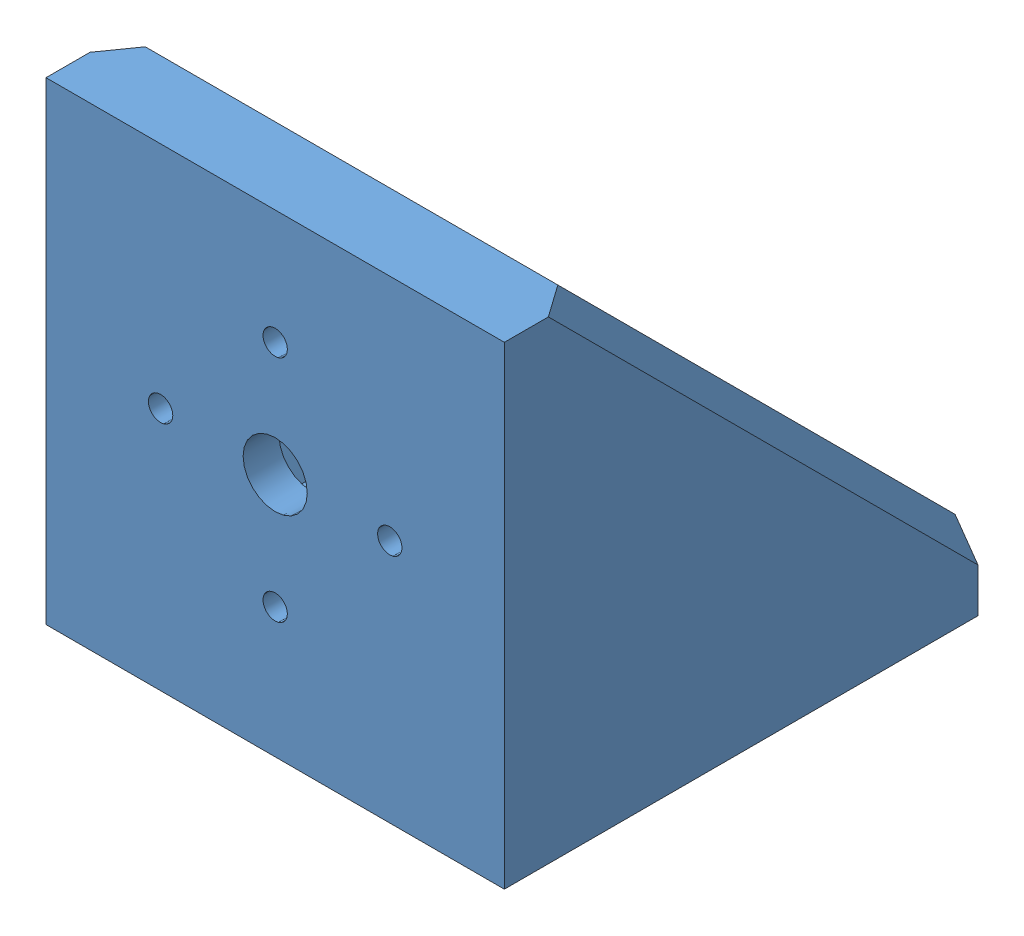
SolidWorks assembly Mounting_Bracket_Assembly_P, configuration Default. Lengths in mm.
Overall size (60 62 62).
9 component instances, 2 part files, 24 mates.
Components (placement in the parent):
- Mounting_Bracket_P-1: Mounting_Bracket_P [Default] at (-10.4197 -1.1809 82.1931) size (60 62 62)
- M3 x 0.5 Hex Nut-1: M3 x 0.5 Hex Nut [90592A085] at (19.5803 45.8191 74.4931) x (0 -1 0) z (1 0 0) size (5.5 2.98 6.35)
- M3 x 0.5 Hex Nut-2: M3 x 0.5 Hex Nut [90592A085] at (4.5803 30.8191 74.4931) x (-0.5 0.866025 0) z (-0.866025 -0.5 0) size (5.5 2.98 6.35)
- M3 x 0.5 Hex Nut-3: M3 x 0.5 Hex Nut [90592A085] at (34.5803 30.8191 74.4931) x (-0.5 0.866025 0) z (-0.866025 -0.5 0) size (5.5 2.98 6.35)
- M3 x 0.5 Hex Nut-4: M3 x 0.5 Hex Nut [90592A085] at (19.5803 15.8191 74.4931) x (0 -1 0) z (1 0 0) size (5.5 2.98 6.35)
- M3 x 0.5 Hex Nut-5: M3 x 0.5 Hex Nut [90592A085] at (34.5803 6.5191 50.1931) x (-0.5 0 -0.866025) z (0.866025 0 -0.5) size (5.5 2.98 6.35)
- M3 x 0.5 Hex Nut-6: M3 x 0.5 Hex Nut [90592A085] at (4.5803 6.5191 50.1931) x (0.5 0 -0.866025) z (0.866025 0 0.5) size (5.5 2.98 6.35)
- M3 x 0.5 Hex Nut-7: M3 x 0.5 Hex Nut [90592A085] at (19.5803 6.5191 35.1931) x (-0.866025 0 -0.5) z (0.5 0 -0.866025) size (5.5 2.98 6.35)
- M3 x 0.5 Hex Nut-8: M3 x 0.5 Hex Nut [90592A085] at (19.5803 6.5191 65.1931) x (0 0 -1) z (1 0 0) size (5.5 2.98 6.35)
Mates (geometry in assembly coordinates):
- Concentric1: concentric anti-aligned: circle of Mounting_Bracket_P-1; circle of M3 x 0.5 Hex Nut-1
- Concentric2: concentric anti-aligned: circle of Mounting_Bracket_P-1; circle of M3 x 0.5 Hex Nut-2
- Concentric3: concentric anti-aligned: circle of Mounting_Bracket_P-1; circle of M3 x 0.5 Hex Nut-3
- Concentric5: concentric anti-aligned: circle of Mounting_Bracket_P-1; circle of M3 x 0.5 Hex Nut-4
- Parallel1: parallel aligned: plane of Mounting_Bracket_P-1 through (37.4303 29.1736 75.6931) normal (-0.5 0.866025 0); plane of M3 x 0.5 Hex Nut-3 through (31.8303 32.4068 73.2931) normal (-0.5 0.866025 0)
- Parallel2: parallel anti-aligned: plane of Mounting_Bracket_P-1 through (22.8712 45.8191 75.6931) normal (-0.866025 0.5 0); plane of M3 x 0.5 Hex Nut-1 through (22.7557 45.8191 73.2931) normal (0.866025 -0.5 0)
- Parallel3: parallel anti-aligned: plane of Mounting_Bracket_P-1 through (7.4303 29.1736 75.6931) normal (-0.5 0.866025 0); plane of M3 x 0.5 Hex Nut-2 through (7.3303 29.2314 73.2931) normal (0.5 -0.866025 0)
- Parallel5: parallel anti-aligned: plane of Mounting_Bracket_P-1 through (22.8712 15.8191 75.6931) normal (-0.866025 0.5 0); plane of M3 x 0.5 Hex Nut-4 through (22.7557 15.8191 73.2931) normal (0.866025 -0.5 0)
- Coincident6: coincident anti-aligned: plane of Mounting_Bracket_P-1 through (-10.4197 -1.1809 75.6931) normal (0 0 -1); plane of M3 x 0.5 Hex Nut-3 through (37.3303 29.2314 75.6931) normal (0 0 1)
- Coincident7: coincident anti-aligned: plane of Mounting_Bracket_P-1 through (-10.4197 -1.1809 75.6931) normal (0 0 -1); plane of M3 x 0.5 Hex Nut-1 through (17.9926 48.5691 75.6931) normal (0 0 1)
- Coincident8: coincident anti-aligned: plane of Mounting_Bracket_P-1 through (-10.4197 -1.1809 75.6931) normal (0 0 -1); plane of M3 x 0.5 Hex Nut-2 through (7.3303 29.2314 75.6931) normal (0 0 1)
- Coincident9: coincident anti-aligned: plane of Mounting_Bracket_P-1 through (-10.4197 -1.1809 75.6931) normal (0 0 -1); plane of M3 x 0.5 Hex Nut-4 through (17.9926 18.5691 75.6931) normal (0 0 1)
- Concentric6: concentric aligned: circle of Mounting_Bracket_P-1; circle of M3 x 0.5 Hex Nut-8
- Concentric7: concentric aligned: circle of Mounting_Bracket_P-1; circle of M3 x 0.5 Hex Nut-6
- Concentric8: concentric aligned: circle of Mounting_Bracket_P-1; circle of M3 x 0.5 Hex Nut-7
- Concentric9: concentric aligned: circle of Mounting_Bracket_P-1; circle of M3 x 0.5 Hex Nut-5
- Parallel6: parallel anti-aligned: plane of Mounting_Bracket_P-1 through (34.5803 5.3191 53.484) normal (0.5 0 -0.866025); plane of M3 x 0.5 Hex Nut-5 through (31.8303 7.7191 51.7808) normal (-0.5 0 0.866025)
- Parallel7: parallel anti-aligned: plane of Mounting_Bracket_P-1 through (17.9349 5.3191 68.0431) normal (0.866025 0 -0.5); plane of M3 x 0.5 Hex Nut-8 through (16.4049 7.7191 65.1931) normal (-0.866025 0 0.5)
- Parallel8: parallel anti-aligned: plane of M3 x 0.5 Hex Nut-6 through (4.5803 7.7191 53.3685) normal (0.5 0 0.866025); plane of Mounting_Bracket_P-1 through (7.4303 5.3191 51.8386) normal (-0.5 0 -0.866025)
- Parallel9: parallel anti-aligned: plane of Mounting_Bracket_P-1 through (21.2258 5.3191 38.0431) normal (0 0 -1); plane of M3 x 0.5 Hex Nut-7 through (17.9926 7.7191 37.9431) normal (0 0 1)
- Coincident14: coincident anti-aligned: plane of Mounting_Bracket_P-1 through (-10.4197 5.3191 82.1931) normal (0 1 0); plane of M3 x 0.5 Hex Nut-5 through (34.5803 5.3191 53.3685) normal (0 -1 0)
- Coincident15: coincident anti-aligned: plane of Mounting_Bracket_P-1 through (-10.4197 5.3191 82.1931) normal (0 1 0); plane of M3 x 0.5 Hex Nut-7 through (21.168 5.3191 37.9431) normal (0 -1 0)
- Coincident16: coincident anti-aligned: plane of Mounting_Bracket_P-1 through (-10.4197 5.3191 82.1931) normal (0 1 0); plane of M3 x 0.5 Hex Nut-6 through (1.8303 5.3191 51.7808) normal (0 -1 0)
- Coincident17: coincident anti-aligned: plane of Mounting_Bracket_P-1 through (-10.4197 5.3191 82.1931) normal (0 1 0); plane of M3 x 0.5 Hex Nut-8 through (17.9926 5.3191 67.9431) normal (0 -1 0)
